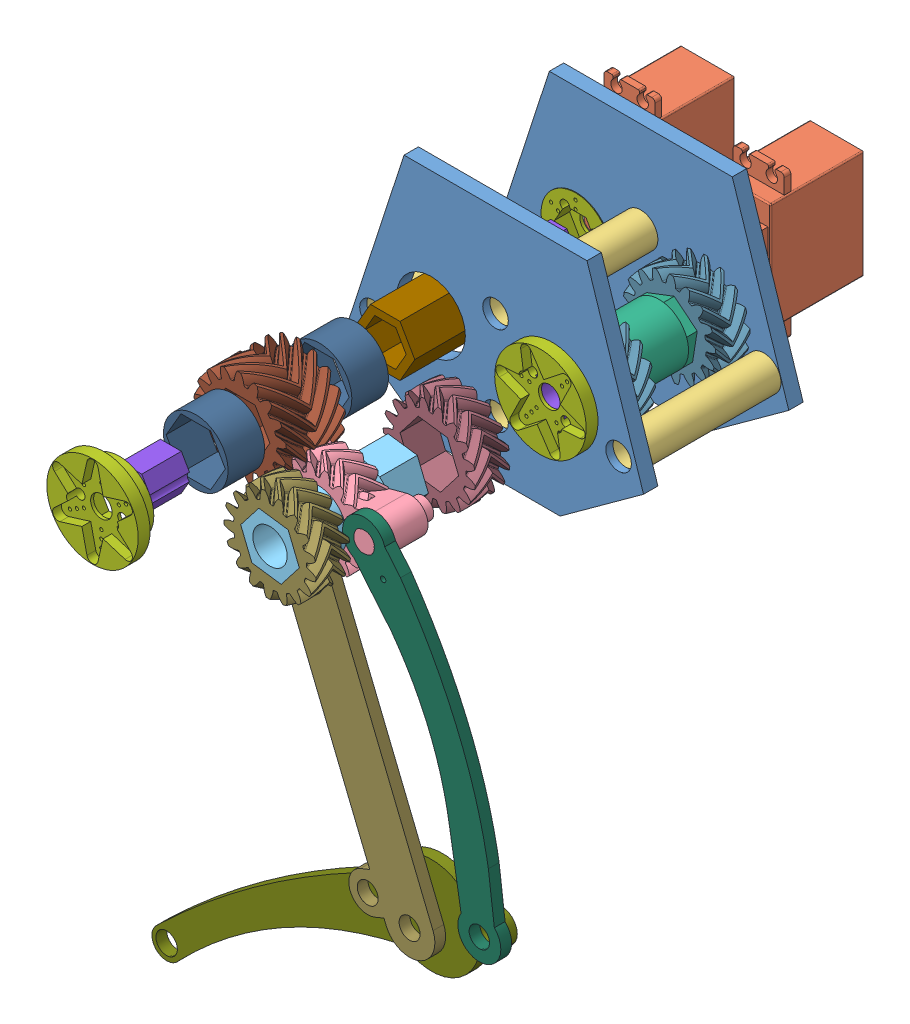
SolidWorks assembly HipGearBoxv01, configuration Default. Lengths in mm.
Overall size (159.06 243.1 230.98).
29 component instances, 16 part files, 89 mates.
Components (placement in the parent):
- GearBoxPlatev01-1: GearBoxPlatev01 [Default] at origin size (110.05 87.22 5.33)
- MG995R Dogv00-1: MG995R Dogv00 [Default] at (24 30.7741 -27.3658) x (0 1 0) z (1 0 0) size (54.05 45.33 20.04)
- MG995R Dogv00-2: MG995R Dogv00 [Default] at (-24 30.7741 -27.3658) x (0 1 0) z (1 0 0) size (54.05 45.33 20.04)
- GearAxelv01-1: GearAxelv01 [Default] at (0 0 2.667) x (0.951994 -0.306118 0) z (0 0 1) size (12.7 12.7 54)
- GearAxelv01-2: GearAxelv01 [Default] at (-45.7517 9.8488 2.667) size (12.7 12.7 54)
- GearAxelv01-3: GearAxelv01 [Default] at (0 33.0087 2.667) size (12.7 12.7 54)
- GearAxelv01-4: GearAxelv01 [Default] at (45.7517 9.8488 2.667) size (12.7 12.7 54)
- GearBoxPlatev01-2: GearBoxPlatev01 [Default] at (0 0 59.334) x (-1 0 0) z (0 0 -1) size (110.05 87.22 5.33)
- QuadDHG001-1: QuadDHG001 [PreviewCfg] at (0 0 119.1679) x (0 0 -1) z (0.704756 0.70945 0) size (55.45 52.13 49.37)
- HexShaft-1: HexShaft [Default] at (0 0 119.1679) x (0.789712 -0.613478 0) z (0 0 1) size (22 22 48)
- HexShaftThighDrive-1: HexShaftThighDrive [Default] at (24 20.2087 32.581) x (-0.357595 0.933877 0) z (0 0 1) size (22 22 48)
- HornAdapterCap04-2: HornAdapterCap04 [Default] at (-24 20.2087 185.1533) x (-1 0.000794 0) z (0 0 -1) size (34 34 10)
- HornAdapterCapCuppler04-2: HornAdapterCapCuppler04 [Default] at (-24 20.2087 174.0177) x (1 -0.000794 0) z (0 0 -1) size (13.84 13.51 14.72)
- HexShaftQuadDrive-1: HexShaftQuadDrive [Default] at (-24 20.2087 52.3463) x (-0.866422 -0.499312 0) z (0 0 1) size (19.05 22 48)
- HornAdapterCap04-3: HornAdapterCap04 [Default] at (-24 20.2087 -4.4) x (-0.499312 0.866422 0) z (0 0 1) size (34 34 10)
- HornAdapterCapCuppler04-3: HornAdapterCapCuppler04 [Default] at (-24 20.2087 9.4164) x (-0.499312 0.866422 0) z (0 0 1) size (13.84 13.51 14.72)
- HexShaftQuadDriveSpacer-1: HexShaftQuadDriveSpacer [Default] at (-24 20.2087 93.9572) x (0.865628 -0.500688 0) z (0 0 1) size (24 24 13.6)
- DriveQuadDHG001-2: DriveQuadDHG001 [PreviewCfg] at (-24 20.2087 119.2168) x (0 0 1) z (-0.865628 0.500688 0) size (55.45 51.54 46.68)
- HexShaftQuadDriveSpacer-2: HexShaftQuadDriveSpacer [Default] at (-24 20.2087 139.9745) x (0.000794 1 0) z (0 0 1) size (24 24 13.6)
- HornAdapterCap04-4: HornAdapterCap04 [Default] at (24 20.2087 -4.4) x (0.776625 -0.629964 0) z (0 0 1) size (34 34 10)
- HornAdapterCapCuppler04-4: HornAdapterCapCuppler04 [Default] at (24 20.2087 -0.392) x (0.776625 -0.629964 0) z (0 0 1) size (13.84 13.51 14.72)
- OuterThigh_DHG001-1: OuterThigh_DHG001 [PreviewCfg] at (0 0 136.7679) x (0 0 -1) z (0.926143 0.377171 0) size (50.85 157.97 46.68)
- InnerThigh_DHG001-1: InnerThigh_DHG001 [PreviewCfg] at (0 0 77.5251) x (0 0 -1) z (0.926143 0.377171 0) size (50.85 157.97 46.68)
- HornAdapterCap04-5: HornAdapterCap04 [Default] at (24 20.2087 66.6449) x (0.776625 -0.629964 0) z (0 0 -1) size (34 34 10)
- HornAdapterCapCuppler04-5: HornAdapterCapCuppler04 [Default] at (24 20.2087 65.521) x (0.776625 -0.629964 0) z (0 0 -1) size (13.84 13.51 14.72)
- DHGSides001-1: DHGSides001 [PreviewCfg] at (24 20.2087 12.2268) x (0 0 1) z (0.357595 -0.933877 0) size (50.85 51.53 46.68)
- DHGSides001-2: DHGSides001 [PreviewCfg] at (24 20.2087 47.4836) x (0 0 1) z (0.357595 -0.933877 0) size (50.85 51.53 46.68)
- RearQuads001-1: RearQuads001 [Default] at (22.5622 -9.2229 128.1679) x (-0.906363 -0.422501 0) z (0 0 -1) size (28.65 129.96 4)
- RearShin001-1: RearShin001 [Default] at (43.0855 -105.7963 124.1679) x (-0.978086 -0.208202 0) z (0 0 1) size (142.58 65.62 4)
Mates (geometry in assembly coordinates):
- Coincident7: coincident aligned: plane of GearBoxPlatev01-1 through (0 0 0) normal (1 0 0)
- Coincident8: coincident aligned: plane of GearBoxPlatev01-1 through (0 0 0) normal (0 1 0)
- Coincident9: coincident aligned: plane of GearBoxPlatev01-1 through (0 0 0) normal (0 0 1)
- Concentric8: concentric anti-aligned: cylinder of GearBoxPlatev01-1 through (24 20.2087 5.334) axis (0 0 -1) radius 12.8; cylinder of MG995R Dogv00-1 through (24 20.2087 -0.5) axis (0 0 1) radius 1.25
- Coincident10: coincident anti-aligned: plane of GearBoxPlatev01-1 through (0 0 2.667) normal (0 0 1); plane of GearAxelv01-1 through (0 0 2.667) normal (0 0 -1)
- Concentric9: concentric aligned: cylinder of GearBoxPlatev01-1 through (0 0 5.334) axis (0 0 -1) radius 4.7625; cylinder of GearAxelv01-1 through (0 0 56.667) axis (0 0 -1) radius 5.334
- Concentric11: concentric anti-aligned: cylinder of GearBoxPlatev01-1 through (-45.7517 9.8488 2.667) axis (0 0 1) radius 6.35; cylinder of GearAxelv01-2 through (-45.7517 9.8488 56.667) axis (0 0 -1) radius 5.334
- Concentric12: concentric anti-aligned: cylinder of GearBoxPlatev01-1 through (0 33.0087 2.667) axis (0 0 1) radius 6.35; cylinder of GearAxelv01-3 through (0 33.0087 56.667) axis (0 0 -1) radius 5.334
- Concentric13: concentric anti-aligned: cylinder of GearBoxPlatev01-1 through (45.7517 9.8488 2.667) axis (0 0 1) radius 6.35; cylinder of GearAxelv01-4 through (45.7517 9.8488 56.667) axis (0 0 -1) radius 5.334
- Coincident12: coincident anti-aligned: plane of GearBoxPlatev01-1 through (45.7517 9.8488 2.667) normal (0 0 1); plane of GearAxelv01-4 through (45.7517 9.8488 2.667) normal (0 0 -1)
- Coincident13: coincident anti-aligned: plane of GearBoxPlatev01-1 through (0 33.0087 2.667) normal (0 0 1); plane of GearAxelv01-3 through (0 33.0087 2.667) normal (0 0 -1)
- Coincident14: coincident anti-aligned: plane of GearBoxPlatev01-1 through (-45.7517 9.8488 2.667) normal (0 0 1); plane of GearAxelv01-2 through (-45.7517 9.8488 2.667) normal (0 0 -1)
- Concentric14: concentric anti-aligned: cylinder of GearAxelv01-1 through (0 0 56.667) axis (0 0 -1) radius 5.334; cylinder of GearBoxPlatev01-2 through (0 0 54) axis (0 0 1) radius 4.7625
- Concentric15: concentric aligned: cylinder of GearAxelv01-3 through (0 33.0087 56.667) axis (0 0 -1) radius 5.334; cylinder of GearBoxPlatev01-2 through (0 33.0087 59.334) axis (0 0 -1) radius 4.7625
- Coincident15: coincident anti-aligned: plane of GearAxelv01-1 through (0 0 56.667) normal (0 0 1); plane of GearBoxPlatev01-2 through (0 0 56.667) normal (0 0 -1)
- LimitDistance21: limit distance = 89.5009 mm aligned: plane of QuadDHG001-1 through (0 0 119.1679) normal (0 0 -1)
- Concentric19: concentric aligned: cylinder of GearAxelv01-1 through (0 0 56.667) axis (0 0 -1) radius 6.35; cylinder of HexShaft-1 through (0 0 129.1679) axis (0 0 -1) radius 6.4
- LimitDistance3: limit distance = 81.1277 mm: plane of assembly through (0 0 29.667) normal (0 0 -1); plane of HexShaft-1 through (0 0 119.1679) normal (0 0 1); plane of assembly
- Concentric20: concentric aligned: cylinder of QuadDHG001-1 through (0 0 125.5679) axis (0 0 -1) radius 11; cylinder of HexShaft-1 through (0 0 129.1679) axis (0 0 -1) radius 11
- LimitDistance20: limit distance = 2.914 mm anti-aligned: plane of HexShaftThighDrive-1 through (24 20.2087 32.581) normal (0 0 1)
- GearMate2: gear = 22 : 22 mm: cylinder of HexShaftThighDrive-1 through (24 20.2087 42.581) axis (0 0 -1) radius 11; cylinder of HexShaft-1 through (0 0 129.1679) axis (0 0 -1) radius 11
- Concentric22: concentric aligned: cylinder of GearBoxPlatev01-2 through (-24 20.2087 54) axis (0 0 1) radius 12.8; cylinder of HornAdapterCap04-2 through (-24 20.2087 175.1533) axis (0 0 1) radius 12.8
- LimitDistance2: limit distance = 121.4193 mm anti-aligned: plane of GearBoxPlatev01-2 through (0 0 59.334) normal (0 0 1); plane of HornAdapterCap04-2 through (-24 20.2087 180.7533) normal (0 0 -1)
- Coincident43: coincident anti-aligned: plane of HornAdapterCap04-2 through (-20.1054 13.4506 201.3901) normal (0.000794 1 0); plane of HornAdapterCapCuppler04-2 through (-20.1054 13.4506 156.0177) normal (-0.000794 -1 0)
- Coincident44: coincident anti-aligned: plane of HornAdapterCap04-2 through (-16.2 20.2025 201.3901) normal (-0.865628 0.500688 0); plane of HornAdapterCapCuppler04-2 through (-16.2 20.2025 156.0177) normal (0.865628 -0.500688 0)
- LimitDistance5: limit distance = 10.0192 mm anti-aligned: plane of HornAdapterCap04-2 through (-24 20.2087 180.7533) normal (0 0 -1); plane of HornAdapterCapCuppler04-2 through (-24 20.2087 170.7341) normal (0 0 1)
- Coincident46: coincident anti-aligned: plane of HornAdapterCapCuppler04-2 through (-16.2 20.2025 156.0177) normal (0.865628 -0.500688 0); plane of HexShaftQuadDrive-1 through (-20.1054 13.4506 28.3463) normal (-0.865628 0.500688 0)
- Coincident48: coincident anti-aligned: plane of HornAdapterCapCuppler04-2 through (-20.0946 26.9606 156.0177) normal (0.866422 0.499312 0); plane of HexShaftQuadDrive-1 through (-16.2 20.2025 28.3463) normal (-0.866422 -0.499312 0)
- Concentric24: concentric aligned: cylinder of GearBoxPlatev01-1 through (-24 20.2087 5.334) axis (0 0 -1) radius 12.8; cylinder of HornAdapterCap04-3 through (-24 20.2087 5.6) axis (0 0 -1) radius 12.8
- Coincident51: coincident anti-aligned: plane of HornAdapterCap04-3 through (-31.8 20.2149 -20.6369) normal (0.866422 0.499312 0); plane of HornAdapterCapCuppler04-3 through (-31.8 20.2149 27.4164) normal (-0.866422 -0.499312 0)
- Coincident52: coincident anti-aligned: plane of HornAdapterCap04-3 through (-27.8946 26.9668 -20.6369) normal (0.865628 -0.500688 0); plane of HornAdapterCapCuppler04-3 through (-27.8946 26.9668 27.4164) normal (-0.865628 0.500688 0)
- LimitDistance6: limit distance = 12.7 mm anti-aligned: plane of HornAdapterCap04-3 through (-24 20.2087 0) normal (0 0 1); plane of HornAdapterCapCuppler04-3 through (-24 20.2087 12.7) normal (0 0 -1)
- Coincident61: coincident anti-aligned: plane of GearBoxPlatev01-1 through (0 0 0) normal (0 0 -1); plane of HornAdapterCap04-3 through (-24 20.2087 0) normal (0 0 1)
- Coincident54: coincident anti-aligned: plane of HexShaftQuadDrive-1 through (-20.1054 13.4506 28.3463) normal (-0.865628 0.500688 0); plane of HornAdapterCapCuppler04-3 through (-20.1054 13.4506 27.4164) normal (0.865628 -0.500688 0)
- LimitDistance8: limit distance = 7.4792 mm: plane of HexShaftQuadDrive-1 through (-24 20.2087 28.3463) normal (0 0 -1); plane of HornAdapterCap04-3 through (-24 20.2087 5.6) normal (0 0 1)
- LimitDistance10: limit distance = 15.6463 mm aligned: plane of HornAdapterCapCuppler04-3 through (-24 20.2087 12.7) normal (0 0 -1); plane of HexShaftQuadDrive-1 through (-24 20.2087 28.3463) normal (0 0 -1)
- Coincident62: coincident anti-aligned: plane of HexShaftQuadDrive-1 through (-32.2538 15.4521 76.3463) normal (-0.866422 -0.499312 0); plane of HexShaftQuadDriveSpacer-1 through (-32.2538 15.4521 87.1572) normal (0.866422 0.499312 0)
- Coincident63: coincident anti-aligned: plane of HexShaftQuadDrive-1 through (-32.2462 24.9784 76.3463) normal (-0.865628 0.500688 0); plane of HexShaftQuadDriveSpacer-1 through (-32.2462 24.9784 87.1572) normal (0.865628 -0.500688 0)
- Coincident64: coincident anti-aligned: plane of HexShaftQuadDrive-1 through (-32.2462 24.9784 76.3463) normal (-0.865628 0.500688 0); plane of DriveQuadDHG001-2 through (-32.2462 24.9784 108.2168) normal (0.865628 -0.500688 0)
- Coincident65: coincident anti-aligned: plane of HexShaftQuadDrive-1 through (-23.9924 29.735 76.3463) normal (0.000794 1 0); plane of DriveQuadDHG001-2 through (-23.9924 29.735 108.2168) normal (-0.000794 -1 0)
- Coincident66: coincident anti-aligned: plane of HexShaftQuadDrive-1 through (-24.0076 10.6824 76.3463) normal (-0.000794 -1 0); plane of HexShaftQuadDriveSpacer-2 through (-24.0076 10.6824 133.1745) normal (0.000794 1 0)
- Coincident67: coincident anti-aligned: plane of HexShaftQuadDrive-1 through (-15.7538 15.439 76.3463) normal (0.865628 -0.500688 0); plane of HexShaftQuadDriveSpacer-2 through (-15.7538 15.439 133.1745) normal (-0.865628 0.500688 0)
- LimitDistance11: limit distance = 58.8109 mm aligned: plane of HexShaftQuadDriveSpacer-1 through (-24 20.2087 87.1572) normal (0 0 -1); plane of HexShaftQuadDrive-1 through (-24 20.2087 28.3463) normal (0 0 -1)
- LimitDistance12: limit distance = 7.4596 mm anti-aligned: plane of HexShaftQuadDriveSpacer-1 through (-24 20.2087 100.7572) normal (0 0 1); plane of DriveQuadDHG001-2 through (-15.673 -7.6419 108.2168) normal (0 0 -1)
- LimitDistance13: limit distance = 2.9577 mm anti-aligned: plane of DriveQuadDHG001-2 through (-15.673 -7.6419 130.2168) normal (0 0 1); plane of HexShaftQuadDriveSpacer-2 through (-24 20.2087 133.1745) normal (0 0 -1)
- LimitDistance14: limit distance = 15.2517 mm anti-aligned: plane of HexShaftQuadDriveSpacer-2 through (-24 20.2087 146.7745) normal (0 0 1); plane of HornAdapterCap04-2 through (-24 20.2087 175.1533) normal (0 0 -1)
- GearMate3: gear = 68.675 : 68.675 mm: circle of DriveQuadDHG001-2; circle of QuadDHG001-1
- Concentric25: concentric aligned: cylinder of GearBoxPlatev01-1 through (24 20.2087 5.334) axis (0 0 -1) radius 12.8; cylinder of HornAdapterCap04-4 through (24 20.2087 5.6) axis (0 0 -1) radius 12.8
- Coincident71: coincident anti-aligned: plane of HornAdapterCap04-4 through (30.0577 15.295 -20.6369) normal (-0.987558 0.157252 0); plane of HornAdapterCapCuppler04-4 through (30.0577 15.295 17.608) normal (0.987558 -0.157252 0)
- Coincident72: coincident anti-aligned: plane of HornAdapterCapCuppler04-4 through (22.7734 12.5057 17.608) normal (0.357595 -0.933877 0); plane of HornAdapterCap04-4 through (22.7734 12.5057 -20.6369) normal (-0.357595 0.933877 0)
- LimitDistance15: limit distance = 2.8916 mm anti-aligned: plane of HornAdapterCapCuppler04-4 through (24 20.2087 2.8916) normal (0 0 -1); plane of HornAdapterCap04-4 through (24 20.2087 0) normal (0 0 1)
- Coincident81: coincident anti-aligned: plane of GearBoxPlatev01-1 through (0 0 0) normal (0 0 -1); plane of HornAdapterCap04-4 through (24 20.2087 0) normal (0 0 1)
- LimitDistance17: limit distance = 5.6894 mm aligned: plane of HexShaftThighDrive-1 through (24 20.2087 8.581) normal (0 0 -1); plane of HornAdapterCapCuppler04-4 through (24 20.2087 2.8916) normal (0 0 -1)
- Coincident86: coincident anti-aligned: plane of HexShaftThighDrive-1 through (17.9423 25.1224 8.581) normal (0.987558 -0.157252 0); plane of HornAdapterCapCuppler04-4 through (17.9423 25.1224 17.608) normal (-0.987558 0.157252 0)
- Coincident87: coincident anti-aligned: plane of HexShaftThighDrive-1 through (16.7158 17.4194 8.581) normal (0.629964 0.776625 0); plane of HornAdapterCapCuppler04-4 through (16.7158 17.4194 17.608) normal (-0.629964 -0.776625 0)
- LimitDistance22: limit distance = 0.0489 mm anti-aligned: plane of QuadDHG001-1 through (0 0 119.1679) normal (0 0 -1); plane of DriveQuadDHG001-2 through (-24 20.2087 119.2168) normal (0 0 1)
- LimitDistance23: limit distance = 94.3878 mm aligned: plane of HexShaftQuadDrive-1 through (-24 20.2087 76.3463) normal (0 0 1); plane of HornAdapterCapCuppler04-2 through (-24 20.2087 170.7341) normal (0 0 1)
- Coincident88: coincident anti-aligned: plane of InnerThigh_DHG001-1 through (4.1489 -10.1876 83.9251) normal (0.136432 0.990649 0); plane of HexShaft-1 through (-1.2997 -9.4372 143.1679) normal (-0.136432 -0.990649 0)
- Coincident89: coincident anti-aligned: plane of HexShaft-1 through (7.523 -5.8442 143.1679) normal (0.789712 -0.613478 0); plane of InnerThigh_DHG001-1 through (10.8971 -1.5007 83.9251) normal (-0.789712 0.613478 0)
- Coincident90: coincident anti-aligned: plane of HexShaft-1 through (1.2997 9.4372 143.1679) normal (0.136432 0.990649 0); plane of OuterThigh_DHG001-1 through (-4.1489 10.1876 143.1679) normal (-0.136432 -0.990649 0)
- Coincident91: coincident anti-aligned: plane of HexShaft-1 through (-7.523 5.8442 143.1679) normal (-0.789712 0.613478 0); plane of OuterThigh_DHG001-1 through (-10.8971 1.5007 143.1679) normal (0.789712 -0.613478 0)
- Coincident92: coincident aligned: plane of QuadDHG001-1 through (0 0 29.667) normal (0 0 -1)
- LimitDistance24: limit distance = 72.1911 mm anti-aligned: plane of InnerThigh_DHG001-1 through (0 0 77.5251) normal (0 0 -1); plane of GearBoxPlatev01-1 through (0 0 5.334) normal (0 0 1)
- LimitDistance25: limit distance = 11.2 mm anti-aligned: plane of OuterThigh_DHG001-1 through (0 0 136.7679) normal (0 0 -1); plane of QuadDHG001-1 through (-0.7616 -29.0587 125.5679) normal (0 0 1)
- LimitDistance26: limit distance = 46.4427 mm anti-aligned: plane of OuterThigh_DHG001-1 through (-12.0698 -26.4445 130.3679) normal (0 0 -1); plane of InnerThigh_DHG001-1 through (-12.0698 -26.4445 83.9251) normal (0 0 1)
- Concentric26: concentric aligned: cylinder of GearBoxPlatev01-2 through (24 20.2087 54) axis (0 0 1) radius 12.8; cylinder of HornAdapterCap04-5 through (24 20.2087 56.6449) axis (0 0 1) radius 12.8
- Coincident97: coincident anti-aligned: plane of HornAdapterCap04-5 through (16.7158 17.4194 82.8818) normal (0.987558 -0.157252 0); plane of HornAdapterCapCuppler04-5 through (16.7158 17.4194 47.521) normal (-0.987558 0.157252 0)
- Coincident98: coincident anti-aligned: plane of HornAdapterCap04-5 through (17.9423 25.1224 82.8818) normal (0.357595 -0.933877 0); plane of HornAdapterCapCuppler04-5 through (17.9423 25.1224 47.521) normal (-0.357595 0.933877 0)
- LimitDistance27: limit distance = 0.0075 mm anti-aligned: plane of HornAdapterCapCuppler04-5 through (24 20.2087 62.2374) normal (0 0 1); plane of HornAdapterCap04-5 through (24 20.2087 62.2449) normal (0 0 -1)
- LimitDistance28: limit distance = 2.9109 mm anti-aligned: plane of HornAdapterCap04-5 through (24 20.2087 62.2449) normal (0 0 -1); plane of GearBoxPlatev01-2 through (0 0 59.334) normal (0 0 1)
- Coincident102: coincident anti-aligned: plane of HexShaftThighDrive-1 through (25.2266 27.9116 8.581) normal (0.357595 -0.933877 0); plane of HornAdapterCapCuppler04-5 through (17.9423 25.1224 47.521) normal (-0.357595 0.933877 0)
- Coincident103: coincident anti-aligned: plane of HexShaftThighDrive-1 through (31.2842 22.9979 8.581) normal (-0.629964 -0.776625 0); plane of HornAdapterCapCuppler04-5 through (25.2266 27.9116 47.521) normal (0.629964 0.776625 0)
- Coincident104: coincident anti-aligned: plane of HexShaftThighDrive-1 through (33.4078 18.7106 56.581) normal (0.987558 -0.157252 0); plane of DHGSides001-2 through (32.5429 13.2791 41.0836) normal (-0.987558 0.157252 0)
- Coincident105: coincident anti-aligned: plane of HexShaftThighDrive-1 through (27.4065 11.3123 56.581) normal (0.357595 -0.933877 0); plane of DHGSides001-2 through (22.2702 9.3455 41.0836) normal (-0.357595 0.933877 0)
- Coincident106: coincident anti-aligned: plane of HexShaftThighDrive-1 through (17.9988 12.8103 56.581) normal (-0.629964 -0.776625 0); plane of DHGSides001-1 through (13.7274 16.2751 5.8268) normal (0.629964 0.776625 0)
- Coincident107: coincident anti-aligned: plane of HexShaftThighDrive-1 through (14.5922 21.7067 56.581) normal (-0.987558 0.157252 0); plane of DHGSides001-1 through (15.4571 27.1383 5.8268) normal (0.987558 -0.157252 0)
- LimitDistance29: limit distance = 0.2258 mm: plane of assembly through (0 0 12.001) normal (0 0 1); plane of DHGSides001-1 through (24 20.2087 12.2268) normal (0 0 1)
- LimitDistance30: limit distance = 65.2983 mm anti-aligned: plane of DHGSides001-1 through (24 20.2087 12.2268) normal (0 0 1); plane of InnerThigh_DHG001-1 through (0 0 77.5251) normal (0 0 -1)
- LimitDistance31: limit distance = 0.1496 mm aligned: plane of DHGSides001-2 through (24 20.2087 47.4836) normal (0 0 1)
- LimitDistance32: limit distance = 89.2843 mm anti-aligned: plane of DHGSides001-2 through (24 20.2087 47.4836) normal (0 0 1); plane of OuterThigh_DHG001-1 through (0 0 136.7679) normal (0 0 -1)
- LimitDistance33: limit distance = 5.6564 mm aligned: plane of HexShaftThighDrive-1 through (24 20.2087 56.581) normal (0 0 1); plane of HornAdapterCapCuppler04-5 through (24 20.2087 62.2374) normal (0 0 1)
- Coincident108: coincident anti-aligned: plane of MG995R Dogv00-1 through (24 20.2087 -4.4) normal (0 0 1); plane of HornAdapterCap04-4 through (24 20.2087 -4.4) normal (0 0 -1)
- Concentric27: concentric aligned: cylinder of RearQuads001-1 through (21.9738 5.9031 126.1679) axis (0 0 1) radius 3.8; cylinder of QuadDHG001-1 through (21.9738 5.9031 108.1679) axis (0 0 1) radius 3.9
- Coincident109: coincident aligned: plane of RearQuads001-1 through (22.5622 -9.2229 130.1679) normal (0 0 1); plane of QuadDHG001-1 through (0 0 130.1679) normal (0 0 1)
- Concentric28: concentric aligned: cylinder of OuterThigh_DHG001-1 through (43.0855 -105.7963 134.3679) axis (0 0 -1) radius 3.9; cylinder of RearShin001-1 through (43.0855 -105.7963 126.1679) axis (0 0 -1) radius 4
- Concentric29: concentric anti-aligned: cylinder of RearQuads001-1 through (64.8123 -99.8592 126.1679) axis (0 0 1) radius 3.8; cylinder of RearShin001-1 through (64.8123 -99.8592 126.1679) axis (0 0 -1) radius 4
- Coincident116: coincident anti-aligned: plane of HexShaft-1 through (0 0 129.1679) normal (0 0 1); plane of OuterThigh_DHG001-1 through (0 0 129.1679) normal (0 0 -1)
- Coincident117: coincident anti-aligned: plane of QuadDHG001-1 through (0 0 119.1679) normal (0 0 -1); plane of HexShaft-1 through (0 0 119.1679) normal (0 0 1)
- Coincident118: coincident anti-aligned: plane of RearQuads001-1 through (22.5622 -9.2229 126.1679) normal (0 0 -1); plane of RearShin001-1 through (43.0855 -105.7963 126.1679) normal (0 0 1)
